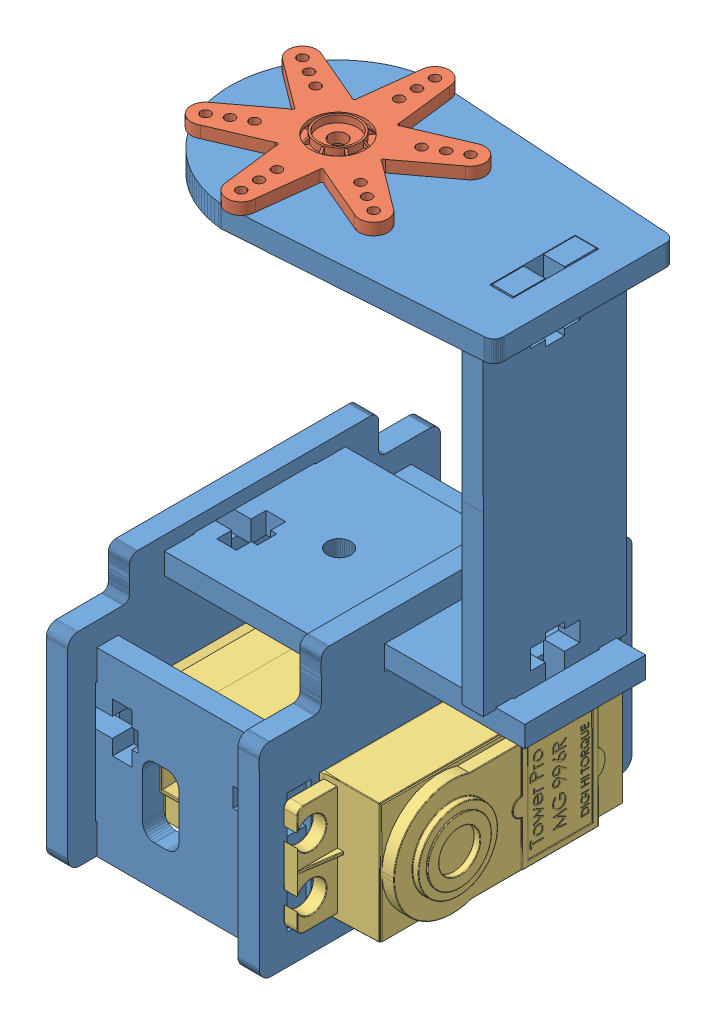
SolidWorks assembly left_hip, configuration Default. Lengths in mm.
Overall size (64.17 96.97 61.03).
4 component instances, 3 part files, 2 mates.
Components (placement in the parent):
- left_hip_100-2: left_hip_100 [Default] at (2.7981 -59.2031 -125.1323) size (57.95 94.6 61.03)
- servo_arm_6_sided-2: servo_arm_6_sided [Default] at (20.9406 35.7187 -94.3997) x (0.866239 0 0.49963) z (-0.49963 0 0.866239) size (36.45 6.25 32.2)
- main_assembly-2: main_assembly [Default] at (-20.2255 -59.2747 -128.7183) x (-0.002628 0.999997 0) z (0.999997 0.002628 0) size (20 53 41.5)
  - main_body-1: main_body [Default] at (15.1003 34.2066 38.7045) size (20 53 41.5)
Mates (geometry in assembly coordinates):
- ProfileCenter1: profile center anti-aligned: circle of left_hip_100-2; circle of servo_arm_6_sided-2
- Coincident3: coincident aligned: line of left_hip_100-2 through (38.4654 -54.0202 -73.8127) axis (0 0 -1); line of main_assembly-2/main_body-1 through (38.4654 -54.0202 -74.7618) axis (0 0 -1)
